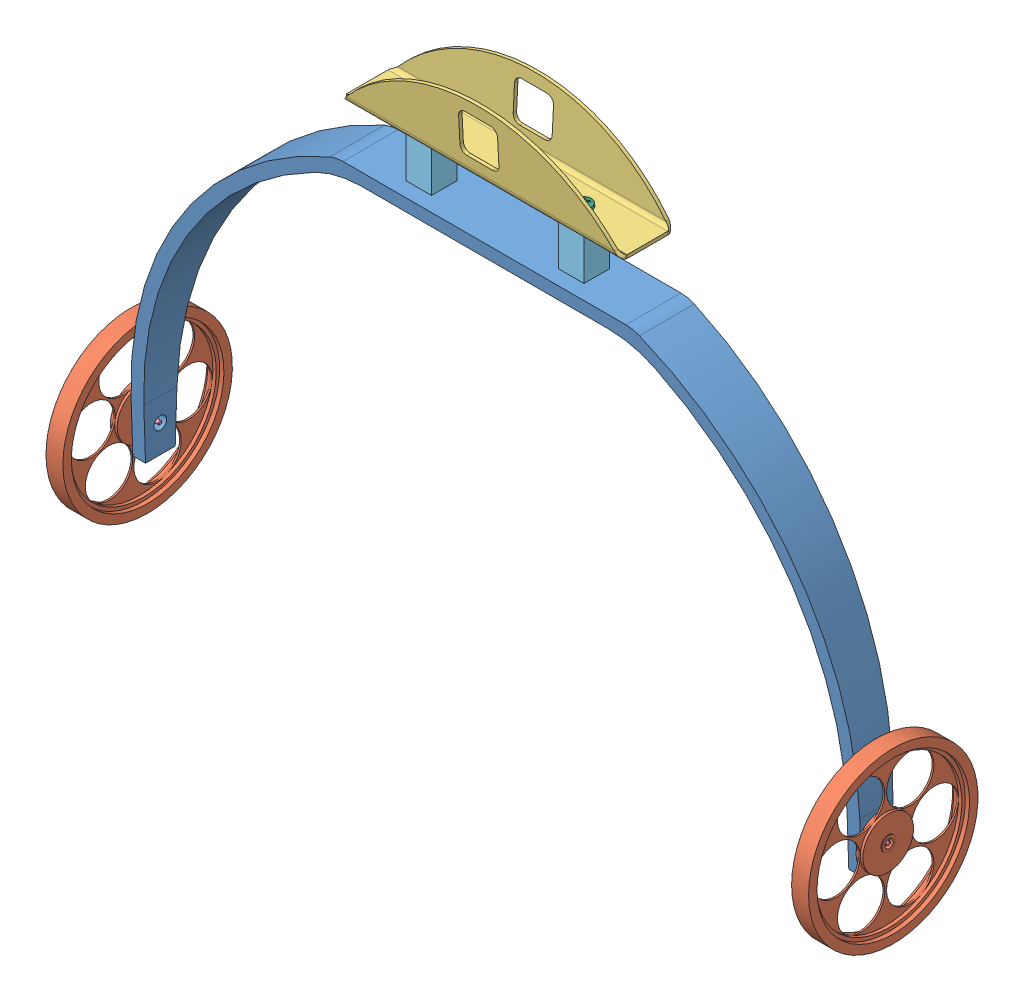
SolidWorks assembly TailGear_Assembly, configuration Default. Lengths in mm.
Overall size (571.5 420.49 145.53).
10 component instances, 6 part files, 22 mates.
Components (placement in the parent):
- TailGear-1: TailGear [Default] at (177.3942 228.0756 483.4818) x (-1 0 0) z (0 0 -1) size (546.1 279.4 110.89)
- 2.5inWheel-1: 2.5inWheel [Default] at (456.7942 248.7131 462.8443) x (0 0 -1) z (1 0 0) size (127 127 12.7)
- 2.5inWheel-2: 2.5inWheel [Default] at (-102.0058 248.7131 462.8443) x (0 0.158553 0.987351) z (-1 0 0) size (127 127 12.7)
- TailGear_Boom_Mount_Sheet-1: TailGear_Boom_Mount_Sheet [Default] at (174.2192 511.6229 497.4746) size (209.56 50.86 45.89)
- dowel pin (hardened production)_ai1-2: dowel pin (hardened production)_ai1 [ASME B18.8.2 - 0.1095x0.75] at (440.9192 248.7131 462.8443) size (19.05 2.78 2.78)
- dowel pin (hardened production)_ai1-3: dowel pin (hardened production)_ai1 [ASME B18.8.2 - 0.1095x0.75] at (-86.1308 248.7131 462.8443) x (-1 0 0) z (0 0.984808 -0.173648) size (19.05 2.78 2.78)
- Spacers-1: Spacers [Default] at (231.3692 507.4756 462.8443) x (-1 0 0) z (0 0 -1) size (19.05 38.1 19.05)
- Spacers-2: Spacers [Default] at (117.0692 507.4756 462.8443) x (0 0 -1) z (1 0 0) size (19.05 38.1 19.05)
- binding head screw_ai-2: binding head screw_ai [CR-BHMS 0.216-24x2x1.5-N] at (231.3692 551.697 462.8443) x (0 -1 0) z (-0.719741 0 0.694243) size (54.34 11.53 11.53)
- binding head screw_ai-3: binding head screw_ai [CR-BHMS 0.216-24x2x1.5-N] at (117.0692 551.697 462.8443) x (0 -1 0) z (0.015235 0 0.999884) size (54.34 11.53 11.53)
Mates (geometry in assembly coordinates):
- Concentric1: concentric aligned: cylinder of TailGear-1 through (450.4442 248.7131 462.8443) axis (-1 0 0) radius 4.7625; cylinder of 2inWheel-1 through (459.9692 248.7131 462.8443) axis (-1 0 0) radius 3.175
- Coincident1: coincident anti-aligned: plane of TailGear-1 through (450.4442 228.0756 442.2068) normal (1 0 0); plane of 2inWheel-1 through (450.4442 248.7131 462.8443) normal (-1 0 0)
- Concentric2: concentric anti-aligned: cylinder of TailGear-1 through (450.4442 248.7131 462.8443) axis (-1 0 0) radius 4.7625; cylinder of 2inWheel-2 through (-105.1808 248.7131 462.8443) axis (1 0 0) radius 3.175
- Coincident2: coincident anti-aligned: plane of TailGear-1 through (-95.6558 228.0756 442.2068) normal (-1 0 0); plane of 2inWheel-2 through (-95.6558 248.7131 462.8443) normal (1 0 0)
- Parallel1: parallel anti-aligned: plane of TailGear-1 through (177.3942 228.0756 483.4818) normal (0 0 -1)
- Concentric3: concentric aligned: cylinder of TailGear-1 through (231.3692 488.9704 462.8443) axis (0 1 0) radius 3.175; cylinder of TailGear_Boom_Mount_Sheet-1 through (231.3692 545.5746 462.8443) axis (0 1 0) radius 3.175
- Parallel4: parallel aligned: plane of TailGear_Boom_Mount_Sheet-1 through (174.2192 511.6229 497.4746) normal (0 0 1)
- Distance1: distance = 38.1 mm anti-aligned: plane of TailGear-1 through (288.5192 507.4756 442.2068) normal (0 1 0); plane of TailGear_Boom_Mount_Sheet-1 through (174.2192 545.5756 529.2375) normal (0 -1 0)
- Concentric4: concentric aligned: cylinder of 2.5inWheel-1 through (457.4292 248.7131 462.8443) axis (-1 0 0) radius 1.5875; cylinder of dowel pin (hardened production)_ai-2 through (434.5692 248.7131 462.8443) axis (-1 0 0) radius 1.3906
- Coincident3: coincident aligned: plane of 2.5inWheel-1 through (459.9692 248.7131 462.8443) normal (1 0 0); plane of dowel pin (hardened production)_ai-2 through (459.9692 248.7131 462.8443) normal (1 0 0)
- Concentric5: concentric aligned: cylinder of 2.5inWheel-2 through (-102.6408 248.7131 462.8443) axis (1 0 0) radius 1.5875; cylinder of dowel pin (hardened production)_ai-3 through (-79.7808 248.7131 462.8443) axis (1 0 0) radius 1.3906
- Coincident4: coincident aligned: plane of 2.5inWheel-2 through (-105.1808 248.7131 462.8443) normal (-1 0 0); plane of dowel pin (hardened production)_ai-3 through (-105.1808 248.7131 462.8443) normal (-1 0 0)
- Concentric6: concentric anti-aligned: cylinder of TailGear_Boom_Mount_Sheet-1 through (231.3692 545.5746 462.8443) axis (0 1 0) radius 3.175; cylinder of Spacers-1 through (231.3692 545.5756 462.8443) axis (0 -1 0) radius 3.175
- Coincident5: coincident anti-aligned: plane of TailGear_Boom_Mount_Sheet-1 through (174.2192 545.5756 529.2375) normal (0 -1 0); plane of Spacers-1 through (231.3692 545.5756 462.8443) normal (0 1 0)
- Concentric7: concentric anti-aligned: cylinder of TailGear_Boom_Mount_Sheet-1 through (117.0692 545.5746 462.8443) axis (0 1 0) radius 3.175; cylinder of Spacers-2 through (117.0692 545.5756 462.8443) axis (0 -1 0) radius 3.175
- Coincident7: coincident anti-aligned: plane of TailGear_Boom_Mount_Sheet-1 through (174.2192 545.5756 529.2375) normal (0 -1 0); plane of Spacers-2 through (117.0692 545.5756 462.8443) normal (0 1 0)
- Parallel9: parallel aligned: plane of Spacers-2 through (126.5942 545.5756 472.3693) normal (0 0 1)
- Parallel10: parallel aligned: plane of Spacers-1 through (240.8942 545.5756 472.3693) normal (0 0 1)
- Concentric8: concentric aligned: cylinder of TailGear_Boom_Mount_Sheet-1 through (231.3692 545.5746 462.8443) axis (0 1 0) radius 3.175; cylinder of binding head screw_ai-2 through (231.3692 577.097 462.8443) axis (0 1 0) radius 2.7432
- Concentric9: concentric aligned: cylinder of TailGear_Boom_Mount_Sheet-1 through (117.0692 545.5746 462.8443) axis (0 1 0) radius 3.175; cylinder of binding head screw_ai-3 through (117.0692 577.097 462.8443) axis (0 1 0) radius 2.7432
- Coincident11: coincident anti-aligned: plane of TailGear_Boom_Mount_Sheet-1 through (174.2192 548.1156 529.2375) normal (0 1 0); plane of binding head screw_ai-3 through (119.8121 548.1156 462.8025) normal (0 -1 0)
- Coincident12: coincident anti-aligned: plane of TailGear_Boom_Mount_Sheet-1 through (174.2192 548.1156 529.2375) normal (0 1 0); plane of binding head screw_ai-2 through (233.2737 548.1156 464.8187) normal (0 -1 0)
